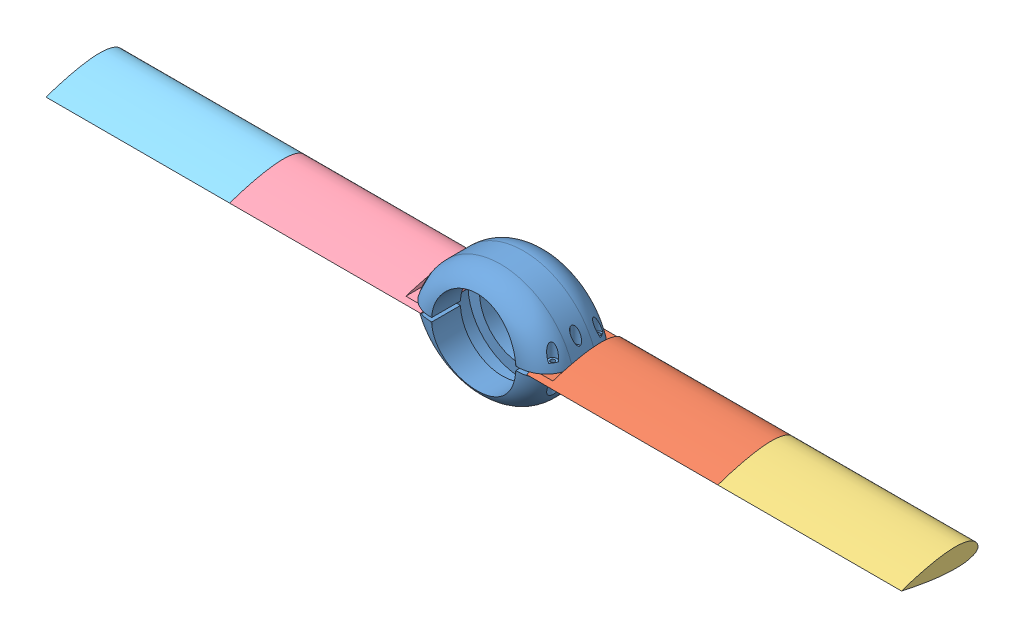
SolidWorks assembly Wing_Assembly, configuration Default. Lengths in mm.
Overall size (1118.12 146 106.33).
6 component instances, 5 part files, 13 mates.
Components (placement in the parent):
- fixWings2 -1: fixWings2  [Default] at origin size (193.16 70.5 106.33)
- fixWings2 -2: fixWings2  [Default] at (0 0 100) x (1 0 0) z (0 0 -1) size (193.16 70.5 106.33)
- Wing1_1-1: Wing1_1 [Default] at (194.0625 0 0) x (0 0 1) z (-1 0 0) size (100 25.05 250)
- Wing1_2-1: Wing1_2 [Default] at (434.0625 0 0) x (0 0 1) z (-1 0 0) size (100 25.05 250)
- Wing2_1-1: Wing2_1 [Default] at (-194.0625 0 -0.0002) x (0 0 1) z (-1 0 0) size (100 25.05 250)
- Wing2_2-1: Wing2_2 [Default] at (-434.0625 0 -0.0002) x (0 0 1) z (-1 0 0) size (100 25.05 250)
Mates (geometry in assembly coordinates):
- Coincident3: coordinate: point of fixWings2 -1
- Coincident4: coincident anti-aligned: plane of fixWings2 -1 through (54.9432 2.5 100) normal (0 -1 0); plane of Wing1_1-1 through (96.0625 2.5 0) normal (0 1 0)
- Concentric1: concentric aligned: cylinder of fixWings2 -2 through (83.0625 -12.5 80) axis (0 1 0) radius 2.75; cylinder of Wing1_1-1 through (83.0625 2.5 80) axis (0 1 0) radius 2.75
- Concentric2: concentric anti-aligned: cylinder of fixWings2 -1 through (83.0625 12.5 20) axis (0 -1 0) radius 2.75; cylinder of Wing1_1-1 through (83.0625 2.5 20) axis (0 1 0) radius 2.75
- Coincident8: coincident anti-aligned: plane of fixWings2 -1 through (-94.0625 2.5 100) normal (0 -1 0); plane of Wing2_1-1 through (-96.0625 2.5 -0.0002) normal (0 1 0)
- Concentric3: concentric anti-aligned: cylinder of fixWings2 -1 through (-83.0625 12.5 20) axis (0 -1 0) radius 2.75; cylinder of Wing2_1-1 through (-83.0625 2.5 20) axis (0 1 0) radius 2.75
- Concentric4: concentric anti-aligned: cylinder of fixWings2 -1 through (-83.0625 12.5 80) axis (0 -1 0) radius 2.75; cylinder of Wing2_1-1 through (-83.0625 2.5 80) axis (0 1 0) radius 2.75
- Coincident9: coincident anti-aligned: plane of Wing2_1-1 through (-309.0625 5 22.4998) normal (0 -1 0); plane of Wing2_2-1 through (-319.0625 5 22.4998) normal (0 1 0)
- Coincident10: coincident anti-aligned: plane of Wing2_1-1 through (-309.0625 5 7.4998) normal (0 0 1); plane of Wing2_2-1 through (-319.0625 -5 7.4998) normal (0 0 -1)
- Coincident11: coincident anti-aligned: plane of Wing2_1-1 through (-309.0625 0 -0.0002) normal (-1 0 0); plane of Wing2_2-1 through (-309.0625 -8.8726 48.5427) normal (1 0 0)
- Coincident12: coincident anti-aligned: plane of Wing1_1-1 through (309.0625 5 22.5) normal (0 -1 0); plane of Wing1_2-1 through (319.0625 5 22.5) normal (0 1 0)
- Coincident13: coincident anti-aligned: plane of Wing1_1-1 through (309.0625 5 7.5) normal (0 0 1); plane of Wing1_2-1 through (319.0625 5 7.5) normal (0 0 -1)
- Coincident14: coincident anti-aligned: plane of Wing1_1-1 through (309.0625 0 0) normal (1 0 0); plane of Wing1_2-1 through (309.0625 -8.8726 48.5429) normal (-1 0 0)
